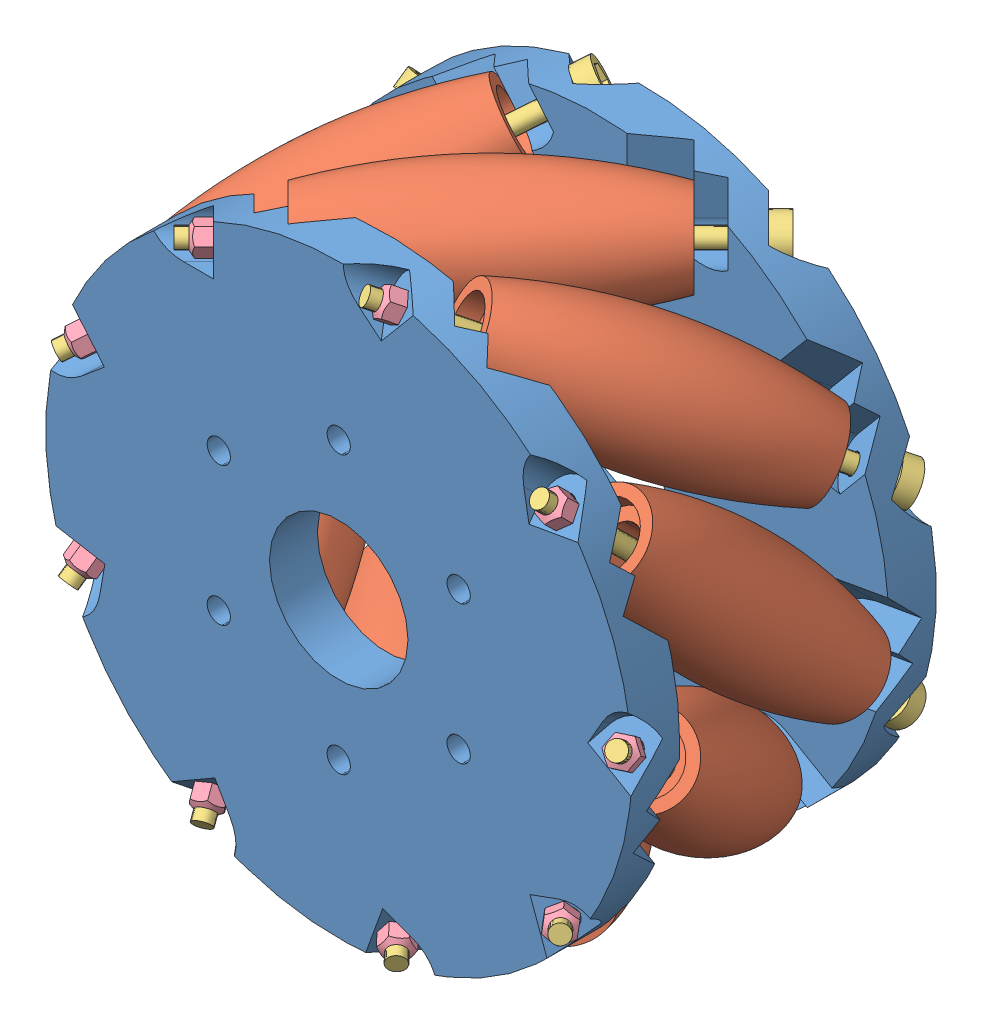
SolidWorks assembly Mecanum wheel assembled, configuration 默认. Lengths in mm.
Overall size (66.84 66.05 34.49).
29 component instances, 4 part files, 14 mates.
Components (placement in the parent):
- Wheel hub-1: Wheel hub [默认] at (-9.1171 -0.067 90.7275) size (58.26 58.26 4.76)
- Roller-1: Roller [默认] at (6.2923 18.0455 113.2863) x (0.828123 0.144222 0.541675) z (-0.541675 0.454519 0.707107) size (11.89 11.89 28.54)
- Wheel hub-4: Wheel hub [默认] at (-9.1171 -0.067 135.5216) x (-1 0 0) z (0 0 -1) size (58.26 58.26 4.76)
- M3x72mm Screw-1: M3x72mm Screw [默认] at (23.8564 3.3075 90.3579) x (0.798276 0.541675 0.263332) z (0.263332 -0.707107 0.656244) size (4.06 43.5 4.06)
- M3 Nut-2: M3 Nut [默认] at (-3.9614 26.6494 126.6715) x (0.798276 0.541675 0.263332) z (0.263332 -0.707107 0.656244) size (3.25 1.74 2.53)
- Roller-10: Roller [默认] at (-8.9554 23.713 113.2863) x (0.541675 0.642788 0.541675) z (-0.707107 0 0.707107) size (11.89 11.89 28.54)
- Roller-11: Roller [默认] at (-24.2787 18.2535 113.2863) x (0.001771 0.840586 0.541675) z (-0.541675 -0.454519 0.707107) size (11.89 11.89 28.54)
- Roller-12: Roller [默认] at (-32.5077 4.2216 113.2863) x (-0.538961 0.645065 0.541675) z (-0.122788 -0.696364 0.707107) size (11.89 11.89 28.54)
- Roller-13: Roller [默认] at (-29.7921 -11.817 113.2863) x (-0.827508 0.147711 0.541675) z (0.353553 -0.612372 0.707107) size (11.89 11.89 28.54)
- Roller-14: Roller [默认] at (-17.4023 -22.3576 113.2863) x (-0.728855 -0.418759 0.541675) z (0.664463 -0.241845 0.707107) size (11.89 11.89 28.54)
- Roller-15: Roller [默认] at (-1.1359 -22.4682 113.2863) x (-0.289162 -0.789287 0.541675) z (0.664463 0.241845 0.707107) size (11.89 11.89 28.54)
- Roller-16: Roller [默认] at (11.3961 -12.0971 113.2863) x (0.285833 -0.790498 0.541675) z (0.353553 0.612372 0.707107) size (11.89 11.89 28.54)
- M3 Nut-11: M3 Nut [默认] at (-22.3405 23.713 126.6715) x (0.263332 0.928069 0.263332) z (0.656244 -0.372408 0.656244) size (3.25 1.74 2.53)
- M3 Nut-12: M3 Nut [默认] at (-34.5323 9.6496 126.6715) x (-0.394827 0.880209 0.263332) z (0.742091 0.136544 0.656244) size (3.25 1.74 2.53)
- M3 Nut-13: M3 Nut [默认] at (-34.8321 -8.9602 126.6715) x (-0.868242 0.420489 0.263332) z (0.480706 0.581606 0.656244) size (3.25 1.74 2.53)
- M3 Nut-14: M3 Nut [默认] at (-23.0995 -23.4089 126.6715) x (-0.935398 -0.235982 0.263332) z (-0.005607 0.754528 0.656244) size (3.25 1.74 2.53)
- M3 Nut-15: M3 Nut [默认] at (-4.8244 -26.9356 126.6715) x (-0.56487 -0.782035 0.263332) z (-0.489296 0.574398 0.656244) size (3.25 1.74 2.53)
- M3 Nut-16: M3 Nut [默认] at (11.4421 -17.8902 126.6715) x (0.069967 -0.962165 0.263332) z (-0.744039 0.125501 0.656244) size (3.25 1.74 2.53)
- M3 Nut-17: M3 Nut [默认] at (18.0887 -0.5052 126.6715) x (0.672065 -0.692087 0.263332) z (-0.650637 -0.38212 0.656244) size (3.25 1.74 2.53)
- M3x72mm Screw-10: M3x72mm Screw [默认] at (13.973 23.713 90.3579) x (0.263332 0.928069 0.263332) z (0.656244 -0.372408 0.656244) size (4.06 43.5 4.06)
- M3x72mm Screw-11: M3x72mm Screw [默认] at (-6.7145 32.9915 90.3579) x (-0.394827 0.880209 0.263332) z (0.742091 0.136544 0.656244) size (4.06 43.5 4.06)
- M3x72mm Screw-12: M3x72mm Screw [默认] at (-28.5263 26.8017 90.3579) x (-0.868242 0.420489 0.263332) z (0.480706 0.581606 0.656244) size (4.06 43.5 4.06)
- M3x72mm Screw-13: M3x72mm Screw [默认] at (-41.2563 8.0396 90.3579) x (-0.935398 -0.235982 0.263332) z (-0.005607 0.754528 0.656244) size (4.06 43.5 4.06)
- M3x72mm Screw-14: M3x72mm Screw [默认] at (-38.948 -14.5156 90.3579) x (-0.56487 -0.782035 0.263332) z (-0.489296 0.574398 0.656244) size (4.06 43.5 4.06)
- M3x72mm Screw-15: M3x72mm Screw [默认] at (-22.6815 -30.3102 90.3579) x (0.069967 -0.962165 0.263332) z (-0.744039 0.125501 0.656244) size (4.06 43.5 4.06)
- M3x72mm Screw-16: M3x72mm Screw [默认] at (-0.0681 -31.9537 90.3579) x (0.672065 -0.692087 0.263332) z (-0.650637 -0.38212 0.656244) size (4.06 43.5 4.06)
- M3x72mm Screw-17: M3x72mm Screw [默认] at (18.3112 -18.677 90.3579) x (0.959697 -0.098174 0.263332) z (-0.252795 -0.710942 0.656244) size (4.06 43.5 4.06)
- M3 Nut-18: M3 Nut [默认] at (12.0054 17.0849 126.6715) x (0.959697 -0.098174 0.263332) z (-0.252795 -0.710942 0.656244) size (3.25 1.74 2.53)
- Roller-17: Roller [默认] at (14.3297 3.903 113.2863) x (0.727083 -0.421827 0.541675) z (-0.122788 0.696364 0.707107) size (11.89 11.89 28.54)
Mates (geometry in assembly coordinates):
- 同心1: concentric aligned: cylinder of M3x72mm Screw-1 through (-7.8903 29.9461 131.8003) axis (-0.541675 0.454519 0.707107) radius 0.87; cylinder of Roller-1 through (14.0209 11.5604 103.1973) axis (-0.541675 0.454519 0.707107) radius 1.7835
- 重合1: coincident anti-aligned: plane of Wheel hub-1 through (14.0209 11.5604 103.1973) normal (-0.541675 0.454519 0.707107); plane of Roller-1 through (3.6368 19.3936 90.2076) normal (0.541675 -0.454519 -0.707107)
- 同心11: concentric aligned: circle of Wheel hub-1; circle of M3x72mm Screw-1
- 重合11: coincident anti-aligned: plane of Wheel hub-1 through (16.8547 9.1826 99.498) normal (0.541675 -0.454519 -0.707107); plane of M3x72mm Screw-1 through (17.5492 9.6538 99.7271) normal (-0.541675 0.454519 0.707107)
- 同心12: concentric aligned: circle of M3x72mm Screw-1; circle of M3 Nut-2
- 同心17: concentric aligned: circle of Wheel hub-1; circle of Roller-1
- 重合19: coincident anti-aligned: plane of Wheel hub-1 through (14.0209 11.5604 103.1973) normal (-0.541675 0.454519 0.707107); plane of Roller-1 through (3.6368 19.3936 90.2076) normal (0.541675 -0.454519 -0.707107)
- 同心19: concentric aligned: circle of Wheel hub-1; circle of M3x72mm Screw-1
- 重合21: coincident anti-aligned: plane of Wheel hub-1 through (16.8547 9.1826 99.498) normal (0.541675 -0.454519 -0.707107); plane of M3x72mm Screw-1 through (17.5492 9.6538 99.7271) normal (-0.541675 0.454519 0.707107)
- 平行2: parallel anti-aligned: plane of Wheel hub-1 through (-9.1171 -0.067 102.747) normal (0 0 1); plane of Wheel hub-4 through (-9.1171 -0.067 123.502) normal (0 0 -1)
- 重合25: coincident anti-aligned: plane of Roller-1 through (-11.8204 32.3637 110.3856) normal (-0.541675 0.454519 0.707107); plane of Wheel hub-4 through (-1.6841 24.7386 123.0518) normal (0.541675 -0.454519 -0.707107)
- 同心20: concentric anti-aligned: cylinder of Wheel hub-1 through (-9.1171 -0.067 97.991) axis (0 0 1) radius 6.8807; cylinder of Wheel hub-4 through (-9.1171 -0.067 128.258) axis (0 0 -1) radius 6.8807
- 同心23: concentric anti-aligned: cylinder of M3x72mm Screw-1 through (-7.8903 29.9461 131.8003) axis (-0.541675 0.454519 0.707107) radius 0.87; cylinder of M3 Nut-2 through (-5.2127 27.6993 128.3049) axis (0.541675 -0.454519 -0.707107) radius 0.87
- 重合26: coincident anti-aligned: plane of Wheel hub-4 through (-4.518 27.1164 126.7511) normal (-0.541675 0.454519 0.707107); plane of M3 Nut-2 through (-4.2702 26.9085 127.0746) normal (0.541675 -0.454519 -0.707107)
